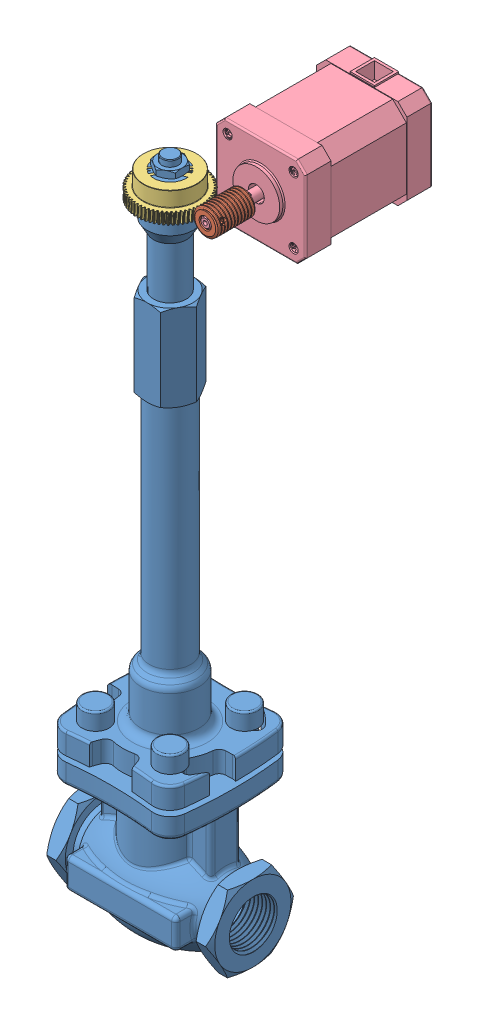
SolidWorks assembly [FS] LOx Control System, configuration Default. Lengths in mm.
Overall size (81.82 322.45 109.81).
4 component instances, 4 part files, 8 mates.
Components (placement in the parent):
- [FS] LOx Control Valve-1: [FS] LOx Control Valve [49415K42] at origin size (79.32 316.17 57.56)
- [FS] 0.5 Module Worm-1: [FS] 0.5 Module Worm [57545K624] at (20.958 278.125 -4.558) x (0.334463 -0.942409 0) z (0 0 1) size (12.31 12.28 18.47)
- [FS] 0.5 Module Worm Gear 60-1-1: [FS] 0.5 Module Worm Gear 60-1 [57545K741] at (0 278.0756 0) x (0.923048 0 0.384684) z (0 -1 0) size (31.47 31.47 12.01)
- [FS] NEMA 17 Stepper Motor-1: [FS] NEMA 17 Stepper Motor [6627T92] at (20.958 278.125 -38.292) size (42.4 43.16 85.47)
Mates (geometry in assembly coordinates):
- Concentric1: concentric aligned: cylinder of [FS] LOx Control Valve-1 through (0 293.8066 0) axis (0 1 0) radius 7.7216; cylinder of [FS] 0.5 Module Worm Gear 60-1-1 through (0 280.2256 0) axis (0 1 0) radius 12.5
- Coincident1: coincident aligned: plane of [FS] LOx Control Valve-1 through (7.7216 287.5756 0) normal (0 1 0); plane of [FS] 0.5 Module Worm Gear 60-1-1 through (0 287.5756 0) normal (0 1 0)
- Concentric3: concentric aligned: cylinder of [FS] 0.5 Module Worm-1 through (20.958 278.125 -13.558) axis (0 0 -1) radius 2.5; cylinder of [FS] NEMA 17 Stepper Motor-1 through (20.958 278.125 4.442) axis (0 0 -1) radius 2.5
- Coincident2: coincident aligned: plane of [FS] 0.5 Module Worm-1 through (20.958 278.125 4.442) normal (0 0 1); plane of [FS] NEMA 17 Stepper Motor-1 through (20.958 278.125 4.442) normal (0 0 1)
- Distance2: distance = 194.31 mm anti-aligned: plane of [FS] LOx Control Valve-1 through (10.5013 62.869 -107.5179) normal (0 1 0); plane of [FS] NEMA 17 Stepper Motor-1 through (6.4381 257.179 -69.1388) normal (0 -1 0)
- Distance3: distance = 15.748 mm aligned: plane of [FS] LOx Control Valve-1 through (26.156 -500000 -7.1398) normal (1 0 0); plane of [FS] NEMA 17 Stepper Motor-1 through (41.904 292.6449 -69.1388) normal (1 0 0)
- Distance4: distance = 21.59 mm aligned: plane of [FS] NEMA 17 Stepper Motor-1 through (20.958 278.125 -21.59) normal (0 0 1); plane of [FS] LOx Control Valve-1 through (0 0 0) normal (0 0 1)
- GearMate1: gear = 25.4 : 1524 mm: cylinder of [FS] 0.5 Module Worm Gear 60-1-1 through (0 280.2256 0) axis (0 1 0) radius 12.5; cylinder of [FS] 0.5 Module Worm-1 through (20.958 278.125 -13.558) axis (0 0 -1) radius 2.5
